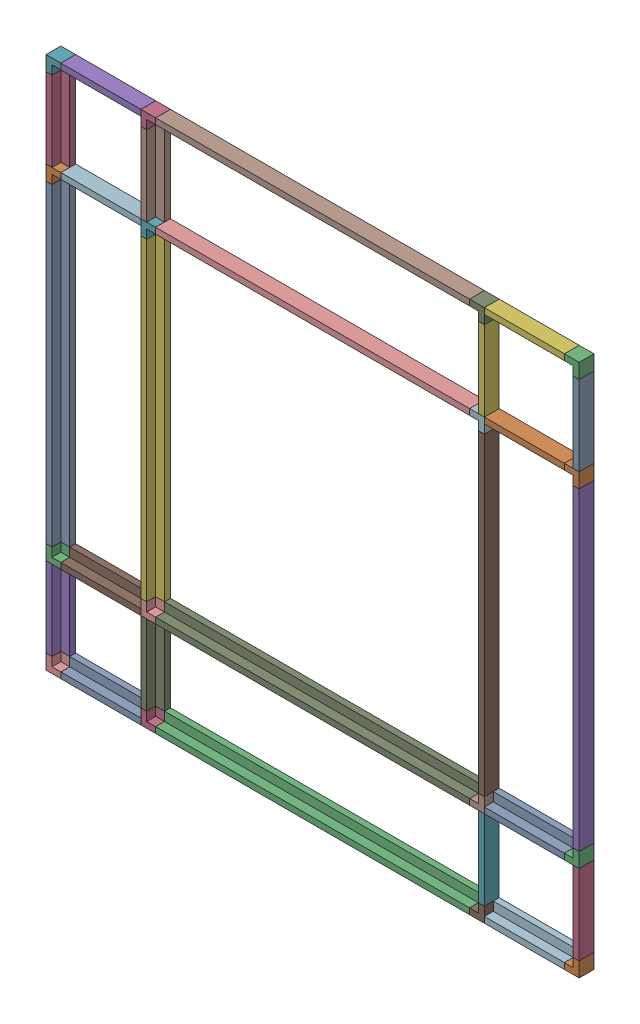
SolidWorks assembly LongBeamAssembly, configuration Default. Lengths in mm.
Overall size (180 180 5).
42 component instances, 3 part files, 86 mates.
Components (placement in the parent):
- Beam106-1: Beam106 [Default] at (9.4821 -22.398 50.0399) size (5 106 5)
- Corner3-1: Corner3 [Default] at (11.6206 86.102 50.8367) x (0 0 1) z (0 -1 0) size (5 5 5)
- Corner3-6: Corner3 [Default] at (11.6206 -24.898 50.8367) x (0 1 0) z (0 0 1) size (5 5 5)
- Beam27-4: Beam27 [Default] at (14.3216 88.602 50.8367) size (5 27 5)
- Beam27-7: Beam27 [Default] at (14.3216 -54.398 50.8367) size (5 27 5)
- Beam106-2: Beam106 [Default] at (41.4821 -22.398 50.0399) size (5 106 5)
- Corner3-14: Corner3 [Default] at (43.6206 86.102 50.8367) x (0 0 1) z (0 -1 0) size (5 5 5)
- Beam27-9: Beam27 [Default] at (46.3216 88.602 50.8367) size (5 27 5)
- Beam27-10: Beam27 [Default] at (46.3216 -54.398 50.8367) size (5 27 5)
- Corner3-16: Corner3 [Default] at (43.6206 -24.898 50.8367) x (0 1 0) z (0 0 1) size (5 5 5)
- Beam106-5: Beam106 [Default] at (152.9174 -22.398 51.1982) x (0 0 1) z (-1 0 0) size (5 106 5)
- Corner3-18: Corner3 [Default] at (152.1206 86.102 53.3367) x (-1 0 0) z (0 -1 0) size (5 5 5)
- Beam27-11: Beam27 [Default] at (184.1206 88.602 56.0378) x (0 0 1) z (-1 0 0) size (5 27 5)
- Corner3-20: Corner3 [Default] at (184.1206 86.102 53.3367) x (-1 0 0) z (0 -1 0) size (5 5 5)
- Corner3-21: Corner3 [Default] at (184.1206 -24.898 53.3367) x (0 1 0) z (-1 0 0) size (5 5 5)
- Beam27-12: Beam27 [Default] at (184.1206 -54.398 56.0378) x (0 0 1) z (-1 0 0) size (5 27 5)
- Beam106-6: Beam106 [Default] at (184.9174 -22.398 51.1982) x (0 0 1) z (-1 0 0) size (5 106 5)
- Beam27-13: Beam27 [Default] at (152.1206 88.602 56.0378) x (0 0 1) z (-1 0 0) size (5 27 5)
- Beam27-14: Beam27 [Default] at (152.1206 -54.398 56.0378) x (0 0 1) z (-1 0 0) size (5 27 5)
- Corner3-24: Corner3 [Default] at (152.1206 -24.898 53.3367) x (0 1 0) z (-1 0 0) size (5 5 5)
- Beam106-7: Beam106 [Default] at (149.6206 -24.5365 50.0399) x (0 1 0) z (0 0 1) size (5 106 5)
- Beam106-8: Beam106 [Default] at (43.6206 85.7405 50.0399) x (0 -1 0) z (0 0 1) size (5 106 5)
- Beam27-15: Beam27 [Default] at (38.6206 -19.6969 50.8367) x (0 1 0) z (0 0 1) size (5 27 5)
- Beam27-16: Beam27 [Default] at (38.6206 86.102 56.0378) x (0 0 1) z (0 -1 0) size (5 27 5)
- Beam27-17: Beam27 [Default] at (154.6206 -24.898 56.0378) x (0 0 1) z (0 1 0) size (5 27 5)
- Beam27-18: Beam27 [Default] at (154.6206 80.901 50.8367) x (0 -1 0) z (0 0 1) size (5 27 5)
- LongBeamAssemblyProper-1: LongBeamAssemblyProper [Default] at (108.4165 -105.7684 38.2187) x (0 1 0) z (0 0 1) size (5 180 5)
  - Corner3-1: Corner3 [Default] at (223.8705 -73.2042 12.618) x (-1 0 0) z (0 0 1) size (5 5 5)
  - Corner3-2: Corner3 [Default] at (223.8705 67.2958 15.118) x (-1 0 0) z (0 -1 0) size (5 5 5)
  - Beam27-1: Beam27 [Default] at (223.8705 69.7958 17.819) x (0 0 1) z (-1 0 0) size (5 27 5)
  - Beam27-2: Beam27 [Default] at (223.8705 -73.2042 17.819) x (0 0 1) z (-1 0 0) size (5 27 5)
  - Corner3-3: Corner3 [Default] at (223.8705 96.7958 12.618) x (0 0 1) z (-1 0 0) size (5 5 5)
  - Beam106-1: Beam106 [Default] at (224.6673 -41.2042 12.9795) x (0 0 1) z (-1 0 0) size (5 106 5)
  - Corner3-4: Corner3 [Default] at (223.8705 -43.7042 15.118) x (0 1 0) z (-1 0 0) size (5 5 5)
- LongBeamAssemblyProper-2: LongBeamAssemblyProper [Default] at (84.8248 166.9725 38.2187) x (0 -1 0) z (0 0 1) size (5 180 5)
  - Corner3-1: Corner3 [Default] at (223.8705 -73.2042 12.618) x (-1 0 0) z (0 0 1) size (5 5 5)
  - Corner3-2: Corner3 [Default] at (223.8705 67.2958 15.118) x (-1 0 0) z (0 -1 0) size (5 5 5)
  - Beam27-1: Beam27 [Default] at (223.8705 69.7958 17.819) x (0 0 1) z (-1 0 0) size (5 27 5)
  - Beam27-2: Beam27 [Default] at (223.8705 -73.2042 17.819) x (0 0 1) z (-1 0 0) size (5 27 5)
  - Corner3-3: Corner3 [Default] at (223.8705 96.7958 12.618) x (0 0 1) z (-1 0 0) size (5 5 5)
  - Beam106-1: Beam106 [Default] at (224.6673 -41.2042 12.9795) x (0 0 1) z (-1 0 0) size (5 106 5)
  - Corner3-4: Corner3 [Default] at (223.8705 -43.7042 15.118) x (0 1 0) z (-1 0 0) size (5 5 5)
Mates (geometry in assembly coordinates):
- Coincident1: coincident anti-aligned: plane of Beam106-1 through (9.4821 -22.398 50.0399) normal (0 -1 0); plane of Corner3-6 through (6.6206 -22.398 48.3367) normal (0 1 0)
- Coincident2: coincident aligned: plane of Beam106-1 through (8.6206 83.602 53.3367) normal (0 0 1); plane of Corner3-6 through (6.6206 -27.398 53.3367) normal (0 0 1)
- Coincident3: coincident aligned: plane of Beam106-1 through (11.6206 83.602 48.3367) normal (1 0 0); plane of Corner3-6 through (11.6206 -24.898 50.8367) normal (1 0 0)
- Coincident6: coincident aligned: plane of Beam106-1 through (7.8893 83.602 48.3367) normal (0 0 -1); plane of Corner3-1 through (6.6206 88.602 48.3367) normal (0 0 -1)
- Coincident7: coincident aligned: plane of Beam106-1 through (8.6206 83.602 53.3367) normal (0 0 1); plane of Corner3-1 through (6.6206 88.602 53.3367) normal (0 0 1)
- Coincident9: coincident anti-aligned: plane of Beam106-1 through (9.4821 83.602 50.0399) normal (0 1 0); plane of Corner3-1 through (6.6206 83.602 48.3367) normal (0 -1 0)
- Coincident10: coincident aligned: plane of Beam106-1 through (6.6206 83.602 53.3367) normal (-1 0 0); plane of Corner3-1 through (6.6206 86.102 50.8367) normal (-1 0 0)
- Coincident12: coincident anti-aligned: plane of Corner3-6 through (6.6206 -27.398 48.3367) normal (0 -1 0); plane of Beam27-7 through (14.3216 -27.398 50.8367) normal (0 1 0)
- Coincident13: coincident aligned: plane of Corner3-6 through (11.6206 -24.898 50.8367) normal (1 0 0); plane of Beam27-7 through (11.6206 -27.398 48.3367) normal (1 0 0)
- Coincident14: coincident aligned: plane of Corner3-6 through (6.6206 -27.398 53.3367) normal (0 0 1); plane of Beam27-7 through (8.6206 -27.398 53.3367) normal (0 0 1)
- Coincident18: coincident anti-aligned: plane of Corner3-1 through (6.6206 88.602 48.3367) normal (0 1 0); plane of Beam27-4 through (14.3216 88.602 50.8367) normal (0 -1 0)
- Coincident19: coincident aligned: plane of Corner3-1 through (6.6206 88.602 53.3367) normal (0 0 1); plane of Beam27-4 through (8.6206 115.602 53.3367) normal (0 0 1)
- Coincident20: coincident aligned: plane of Corner3-1 through (11.6206 86.102 50.8367) normal (1 0 0); plane of Beam27-4 through (11.6206 115.602 48.3367) normal (1 0 0)
- Coincident26: coincident aligned: plane of Corner3-14 through (38.6206 88.602 53.3367) normal (0 0 1); plane of Beam27-9 through (40.6206 115.602 53.3367) normal (0 0 1)
- Coincident27: coincident anti-aligned: plane of Corner3-14 through (38.6206 88.602 48.3367) normal (0 1 0); plane of Beam27-9 through (46.3216 88.602 50.8367) normal (0 -1 0)
- Coincident29: coincident aligned: plane of Beam27-10 through (40.6206 -27.398 53.3367) normal (0 0 1); plane of Corner3-16 through (38.6206 -27.398 53.3367) normal (0 0 1)
- Coincident31: coincident aligned: plane of Corner3-14 through (43.6206 86.102 50.8367) normal (1 0 0); plane of Beam27-9 through (43.6206 115.602 48.3367) normal (1 0 0)
- Coincident32: coincident anti-aligned: plane of Beam27-10 through (46.3216 -27.398 50.8367) normal (0 1 0); plane of Corner3-16 through (38.6206 -27.398 48.3367) normal (0 -1 0)
- Coincident33: coincident anti-aligned: plane of Beam106-2 through (41.4821 83.602 50.0399) normal (0 1 0); plane of Corner3-14 through (38.6206 83.602 48.3367) normal (0 -1 0)
- Coincident36: coincident aligned: plane of Beam106-2 through (39.8893 83.602 48.3367) normal (0 0 -1); plane of Corner3-14 through (38.6206 88.602 48.3367) normal (0 0 -1)
- Coincident37: coincident aligned: plane of Beam106-2 through (40.6206 83.602 53.3367) normal (0 0 1); plane of Corner3-14 through (38.6206 88.602 53.3367) normal (0 0 1)
- Coincident39: coincident aligned: plane of Beam106-2 through (43.6206 83.602 48.3367) normal (1 0 0); plane of Corner3-16 through (43.6206 -24.898 50.8367) normal (1 0 0)
- Coincident40: coincident aligned: plane of Beam106-2 through (38.6206 83.602 53.3367) normal (-1 0 0); plane of Corner3-14 through (38.6206 86.102 50.8367) normal (-1 0 0)
- Coincident41: coincident anti-aligned: plane of Beam106-2 through (41.4821 -22.398 50.0399) normal (0 -1 0); plane of Corner3-16 through (38.6206 -22.398 48.3367) normal (0 1 0)
- Coincident42: coincident aligned: plane of Beam106-2 through (40.6206 83.602 53.3367) normal (0 0 1); plane of Corner3-16 through (38.6206 -27.398 53.3367) normal (0 0 1)
- Coincident43: coincident aligned: plane of Beam27-10 through (43.6206 -27.398 48.3367) normal (1 0 0); plane of Corner3-16 through (43.6206 -24.898 50.8367) normal (1 0 0)
- Coincident45: coincident aligned: plane of Corner3-18 through (149.6206 88.602 48.3367) normal (-1 0 0); plane of Beam27-13 through (149.6206 115.602 50.3367) normal (-1 0 0)
- Coincident46: coincident anti-aligned: plane of Corner3-18 through (154.6206 88.602 48.3367) normal (0 1 0); plane of Beam27-13 through (152.1206 88.602 56.0378) normal (0 -1 0)
- Coincident48: coincident aligned: plane of Corner3-21 through (184.1206 -24.898 53.3367) normal (0 0 1); plane of Beam106-6 through (186.6206 83.602 53.3367) normal (0 0 1)
- Coincident49: coincident aligned: plane of Beam27-11 through (181.6206 115.602 50.3367) normal (-1 0 0); plane of Corner3-20 through (181.6206 88.602 48.3367) normal (-1 0 0)
- Coincident51: coincident aligned: plane of Corner3-21 through (181.6206 -27.398 48.3367) normal (-1 0 0); plane of Beam27-12 through (181.6206 -27.398 50.3367) normal (-1 0 0)
- Coincident52: coincident aligned: plane of Corner3-20 through (186.6206 88.602 48.3367) normal (1 0 0); plane of Beam106-6 through (186.6206 83.602 49.6054) normal (1 0 0)
- Coincident53: coincident anti-aligned: plane of Corner3-20 through (186.6206 83.602 48.3367) normal (0 -1 0); plane of Beam106-6 through (184.9174 83.602 51.1982) normal (0 1 0)
- Coincident56: coincident anti-aligned: plane of Corner3-21 through (186.6206 -27.398 48.3367) normal (0 -1 0); plane of Beam27-12 through (184.1206 -27.398 56.0378) normal (0 1 0)
- Coincident57: coincident anti-aligned: plane of Beam27-11 through (184.1206 88.602 56.0378) normal (0 -1 0); plane of Corner3-20 through (186.6206 88.602 48.3367) normal (0 1 0)
- Coincident58: coincident aligned: plane of Beam27-11 through (186.6206 115.602 53.3367) normal (0 0 1); plane of Corner3-20 through (184.1206 86.102 53.3367) normal (0 0 1)
- Coincident61: coincident aligned: plane of Corner3-20 through (181.6206 88.602 48.3367) normal (-1 0 0); plane of Beam106-6 through (181.6206 83.602 50.3367) normal (-1 0 0)
- Coincident62: coincident anti-aligned: plane of Corner3-21 through (186.6206 -22.398 48.3367) normal (0 1 0); plane of Beam106-6 through (184.9174 -22.398 51.1982) normal (0 -1 0)
- Coincident63: coincident aligned: plane of Corner3-21 through (181.6206 -27.398 48.3367) normal (-1 0 0); plane of Beam106-6 through (181.6206 83.602 50.3367) normal (-1 0 0)
- Coincident64: coincident aligned: plane of Corner3-21 through (184.1206 -24.898 53.3367) normal (0 0 1); plane of Beam27-12 through (186.6206 -27.398 53.3367) normal (0 0 1)
- Coincident65: coincident aligned: plane of Corner3-20 through (184.1206 86.102 48.3367) normal (0 0 -1); plane of Beam106-6 through (181.6206 83.602 48.3367) normal (0 0 -1)
- Coincident67: coincident aligned: plane of Beam27-14 through (149.6206 -27.398 50.3367) normal (-1 0 0); plane of Corner3-24 through (149.6206 -27.398 48.3367) normal (-1 0 0)
- Coincident69: coincident aligned: plane of Corner3-18 through (152.1206 86.102 53.3367) normal (0 0 1); plane of Beam27-13 through (154.6206 115.602 53.3367) normal (0 0 1)
- Coincident70: coincident anti-aligned: plane of Beam27-14 through (152.1206 -27.398 56.0378) normal (0 1 0); plane of Corner3-24 through (154.6206 -27.398 48.3367) normal (0 -1 0)
- Coincident71: coincident anti-aligned: plane of Beam106-5 through (152.9174 83.602 51.1982) normal (0 1 0); plane of Corner3-18 through (154.6206 83.602 48.3367) normal (0 -1 0)
- Coincident74: coincident aligned: plane of Beam106-5 through (154.6206 83.602 49.6054) normal (1 0 0); plane of Corner3-18 through (154.6206 88.602 48.3367) normal (1 0 0)
- Coincident75: coincident aligned: plane of Beam106-5 through (149.6206 83.602 50.3367) normal (-1 0 0); plane of Corner3-18 through (149.6206 88.602 48.3367) normal (-1 0 0)
- Coincident77: coincident aligned: plane of Beam106-5 through (154.6206 83.602 53.3367) normal (0 0 1); plane of Corner3-24 through (152.1206 -24.898 53.3367) normal (0 0 1)
- Coincident78: coincident aligned: plane of Beam106-5 through (149.6206 83.602 48.3367) normal (0 0 -1); plane of Corner3-18 through (152.1206 86.102 48.3367) normal (0 0 -1)
- Coincident79: coincident anti-aligned: plane of Beam106-5 through (152.9174 -22.398 51.1982) normal (0 -1 0); plane of Corner3-24 through (154.6206 -22.398 48.3367) normal (0 1 0)
- Coincident80: coincident aligned: plane of Beam106-5 through (149.6206 83.602 50.3367) normal (-1 0 0); plane of Corner3-24 through (149.6206 -27.398 48.3367) normal (-1 0 0)
- Coincident81: coincident aligned: plane of Beam27-14 through (154.6206 -27.398 53.3367) normal (0 0 1); plane of Corner3-24 through (152.1206 -24.898 53.3367) normal (0 0 1)
- Coincident82: coincident anti-aligned: plane of Corner3-16 through (43.6206 -24.898 50.8367) normal (1 0 0); plane of Beam106-7 through (43.6206 -24.5365 50.0399) normal (-1 0 0)
- Coincident83: coincident aligned: plane of Corner3-16 through (38.6206 -27.398 53.3367) normal (0 0 1); plane of Beam106-7 through (43.6206 -25.398 53.3367) normal (0 0 1)
- Coincident84: coincident aligned: plane of Corner3-16 through (40.6206 -25.398 53.3367) normal (0 1 0); plane of Beam106-7 through (43.6206 -25.398 50.3367) normal (0 1 0)
- Coincident85: coincident anti-aligned: plane of Corner3-14 through (43.6206 86.102 50.8367) normal (1 0 0); plane of Beam106-8 through (43.6206 85.7405 50.0399) normal (-1 0 0)
- Coincident86: coincident aligned: plane of Corner3-14 through (38.6206 88.602 48.3367) normal (0 1 0); plane of Beam106-8 through (149.6206 88.602 53.3367) normal (0 1 0)
- Coincident87: coincident aligned: plane of Corner3-14 through (38.6206 88.602 53.3367) normal (0 0 1); plane of Beam106-8 through (149.6206 86.602 53.3367) normal (0 0 1)
- Coincident88: coincident anti-aligned: plane of Corner3-6 through (11.6206 -24.898 50.8367) normal (1 0 0); plane of Beam27-15 through (11.6206 -19.6969 50.8367) normal (-1 0 0)
- Coincident89: coincident aligned: plane of Corner3-6 through (6.6206 -27.398 53.3367) normal (0 0 1); plane of Beam27-15 through (11.6206 -25.398 53.3367) normal (0 0 1)
- Coincident90: coincident aligned: plane of Corner3-6 through (8.6206 -25.398 53.3367) normal (0 1 0); plane of Beam27-15 through (11.6206 -25.398 50.3367) normal (0 1 0)
- Coincident91: coincident anti-aligned: plane of Corner3-1 through (11.6206 86.102 50.8367) normal (1 0 0); plane of Beam27-16 through (11.6206 86.102 56.0378) normal (-1 0 0)
- Coincident92: coincident aligned: plane of Corner3-1 through (6.6206 88.602 48.3367) normal (0 1 0); plane of Beam27-16 through (11.6206 88.602 49.6054) normal (0 1 0)
- Coincident93: coincident aligned: plane of Corner3-1 through (6.6206 88.602 53.3367) normal (0 0 1); plane of Beam27-16 through (11.6206 88.602 53.3367) normal (0 0 1)
- Coincident95: coincident anti-aligned: plane of Corner3-14 through (38.6206 86.102 50.8367) normal (-1 0 0); plane of Beam27-16 through (38.6206 86.102 56.0378) normal (1 0 0)
- Coincident96: coincident aligned: plane of Corner3-14 through (38.6206 88.602 53.3367) normal (0 0 1); plane of Beam27-16 through (11.6206 88.602 53.3367) normal (0 0 1)
- Coincident97: coincident aligned: plane of Beam106-8 through (149.6206 88.602 53.3367) normal (0 1 0); plane of Beam27-16 through (11.6206 88.602 49.6054) normal (0 1 0)
- Coincident99: coincident anti-aligned: plane of Corner3-24 through (149.6206 -27.398 48.3367) normal (-1 0 0); plane of Beam106-7 through (149.6206 -24.5365 50.0399) normal (1 0 0)
- Coincident100: coincident aligned: plane of Corner3-24 through (152.1206 -24.898 53.3367) normal (0 0 1); plane of Beam106-7 through (43.6206 -25.398 53.3367) normal (0 0 1)
- Coincident101: coincident aligned: plane of Corner3-24 through (154.6206 -27.398 48.3367) normal (0 -1 0); plane of Beam106-7 through (43.6206 -27.398 53.3367) normal (0 -1 0)
- Coincident102: coincident anti-aligned: plane of Corner3-24 through (154.6206 -27.398 48.3367) normal (1 0 0); plane of Beam27-17 through (154.6206 -24.898 56.0378) normal (-1 0 0)
- Coincident103: coincident aligned: plane of Corner3-24 through (154.6206 -27.398 48.3367) normal (0 -1 0); plane of Beam27-17 through (181.6206 -27.398 49.6054) normal (0 -1 0)
- Coincident104: coincident aligned: plane of Corner3-24 through (152.1206 -24.898 53.3367) normal (0 0 1); plane of Beam27-17 through (181.6206 -27.398 53.3367) normal (0 0 1)
- Parallel2: parallel: plane of Corner3-20 through (181.6206 88.602 48.3367) normal (-1 0 0); line of Beam106-6 through (184.6206 83.602 53.3367) axis (0 -1 0)
- Coincident115: coincident anti-aligned: plane of Corner3-20 through (181.6206 88.602 48.3367) normal (-1 0 0); plane of Beam27-18 through (181.6206 80.901 50.8367) normal (1 0 0)
- Coincident116: coincident anti-aligned: plane of Corner3-18 through (154.6206 88.602 48.3367) normal (1 0 0); plane of Beam27-18 through (154.6206 80.901 50.8367) normal (-1 0 0)
- Coincident117: coincident aligned: plane of Corner3-18 through (152.1206 86.102 53.3367) normal (0 0 1); plane of Beam27-18 through (181.6206 86.602 53.3367) normal (0 0 1)
- Coincident118: coincident aligned: plane of Corner3-20 through (184.1206 86.102 53.3367) normal (0 0 1); plane of Beam27-18 through (181.6206 86.602 53.3367) normal (0 0 1)
- Coincident119: coincident aligned: plane of Corner3-18 through (154.6206 88.602 48.3367) normal (0 1 0); plane of Beam27-18 through (181.6206 88.602 53.3367) normal (0 1 0)
- Coincident120: coincident aligned: plane of Corner3-20 through (186.6206 88.602 48.3367) normal (0 1 0); plane of Beam27-18 through (181.6206 88.602 53.3367) normal (0 1 0)
- Coincident121: coincident: plane of Beam27-9 through (46.3216 115.602 50.8367) normal (0 1 0); plane of LongBeamAssemblyProper-1/Corner3-2 through (38.6206 115.602 48.3367) normal (0 -1 0)
- Coincident122: coincident: plane of Beam106-8 through (149.6206 86.602 53.3367) normal (0 0 1); plane of LongBeamAssemblyProper-1/Beam106-1 through (43.6206 120.602 53.3367) normal (0 0 1)
- Coincident123: coincident aligned: plane of Beam27-4 through (6.6206 115.602 53.3367) normal (-1 0 0); plane of LongBeamAssemblyProper-1/Corner3-3 through (6.6206 118.102 50.8367) normal (-1 0 0)
- Coincident124: coincident: plane of Beam27-14 through (152.1206 -54.398 56.0378) normal (0 -1 0); plane of LongBeamAssemblyProper-2/Corner3-2 through (154.6206 -54.398 48.3367) normal (0 1 0)
- Coincident125: coincident: plane of Beam27-10 through (40.6206 -27.398 53.3367) normal (0 0 1); plane of LongBeamAssemblyProper-2/Beam106-1 through (149.6206 -59.398 53.3367) normal (0 0 1)
- Coincident126: coincident aligned: plane of Beam27-7 through (6.6206 -27.398 53.3367) normal (-1 0 0); plane of LongBeamAssemblyProper-2/Corner3-1 through (6.6206 -56.898 50.8367) normal (-1 0 0)
